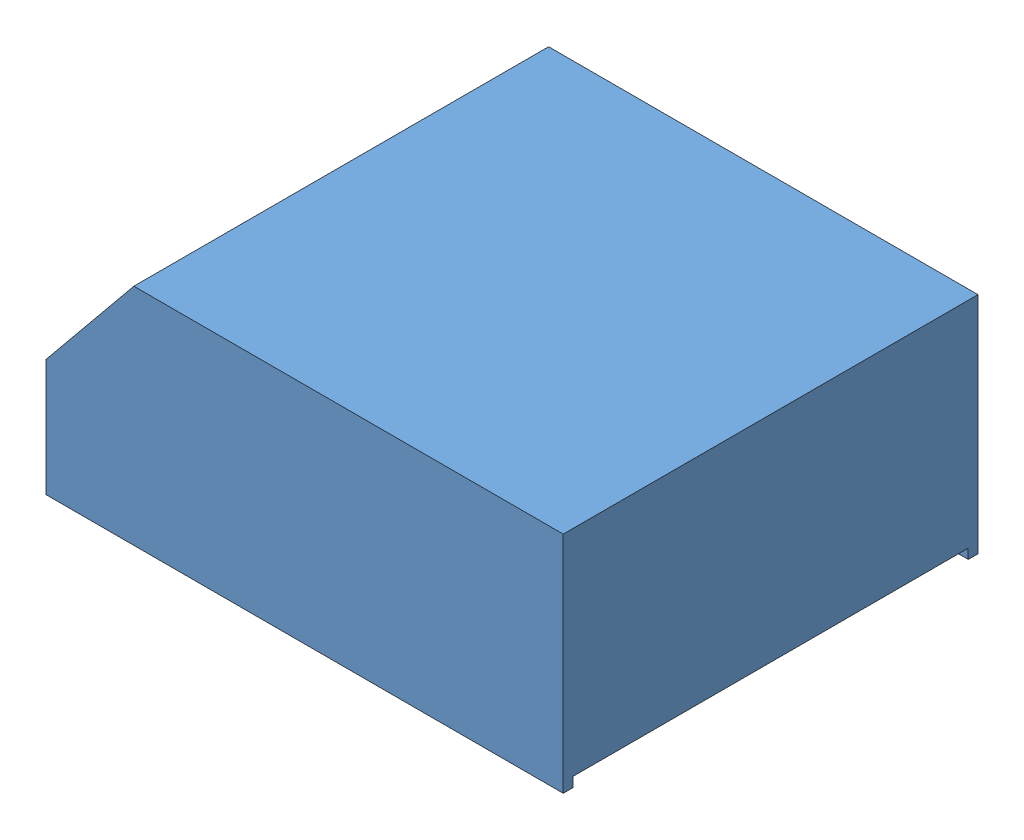
SolidWorks assembly Ensamblaje_Lector de Huellas, configuration Predeterminado. Lengths in mm.
Overall size (106 46 85).
2 component instances, 2 part files, 3 mates.
Components (placement in the parent):
- Lector de Huellas-1: Lector de Huellas [Predeterminado] at (40.4071 -22.2237 63.5) size (106 46 85)
- Lector de Huellas2-1: Lector de Huellas2 [Predeterminado] at (40.4071 -22.2237 65.5) x (0 0 -1) z (1 0 0) size (81 2 104) (hidden)
Mates (geometry in assembly coordinates):
- Coincidente1: coincident: plane of assembly; plane of assembly; plane of Lector de Huellas-1 through (40.4071 -20.2237 63.5) normal (0 -1 0); plane of Lector de Huellas2-1 through (40.4071 -20.2237 65.5) normal (0 1 0)
- Concéntrica1: concentric: cylinder of assembly; cylinder of assembly; cylinder of Lector de Huellas-1 through (-54.5929 -10.2237 133.1) axis (0 -1 0) radius 1.5; cylinder of Lector de Huellas2-1 through (-54.5929 -22.2237 133.1) axis (0 1 0) radius 1.5
- Concéntrica2: concentric: cylinder of assembly; cylinder of assembly; cylinder of Lector de Huellas-1 through (-54.5929 -10.2237 77.6) axis (0 -1 0) radius 1.5; cylinder of Lector de Huellas2-1 through (-54.5929 -22.2237 77.6) axis (0 1 0) radius 1.5
